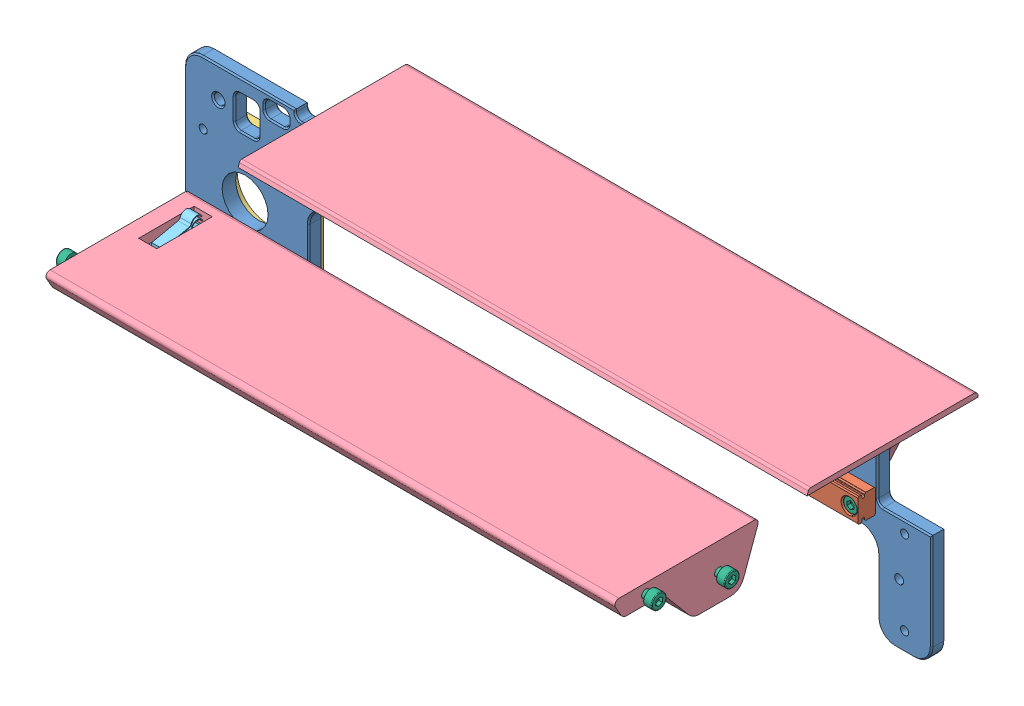
SolidWorks assembly Frame, configuration Default. Lengths in mm.
Overall size (276.5 62.15 134.33).
24 component instances, 6 part files, 47 mates.
Components (placement in the parent):
- Frame plate-1: Frame plate [Default] at (76.4618 160.0978 166.7235) size (276.5 61.25 5)
- Linear rail-1: Linear rail [Default] at (70.7618 160.0978 171.7235) x (0 1 0) z (1 0 0) size (9 6.5 208.9)
- Motor plate-1: Motor plate [Default] at (46.4618 139.3516 166.7235) x (-1 0 0) z (0 0 -1) size (61.5 53.5 20.15)
- Paper tray-1: Paper tray [Default] at (175.2118 177.0978 267.3903) x (0 0 -1) z (1 0 0) size (134.33 22 210.5)
- Limit switch-1: Limit switch [Default] at (79.6118 165.8978 235.3903) x (0 0 -1) z (1 0 0) size (20.1 16 6.3)
- socket head cap screw_din-1: socket head cap screw_din [DIN 912 M3 x 12 --- 12N] at (76.4618 160.0978 177.7235) x (0 0 -1) z (1 0 0) size (15 5.5 5.5)
- socket head cap screw_din-2: socket head cap screw_din [DIN 912 M3 x 12 --- 12N] at (96.4618 160.0978 177.7235) x (0 0 -1) z (1 0 0) size (15 5.5 5.5)
- socket head cap screw_din-3: socket head cap screw_din [DIN 912 M3 x 12 --- 12N] at (116.4618 160.0978 177.7235) x (0 0 -1) z (1 0 0) size (15 5.5 5.5)
- socket head cap screw_din-4: socket head cap screw_din [DIN 912 M3 x 12 --- 12N] at (136.4618 160.0978 177.7235) x (0 0 -1) z (1 0 0) size (15 5.5 5.5)
- socket head cap screw_din-5: socket head cap screw_din [DIN 912 M3 x 12 --- 12N] at (156.4618 160.0978 177.7235) x (0 0 -1) z (1 0 0) size (15 5.5 5.5)
- socket head cap screw_din-6: socket head cap screw_din [DIN 912 M3 x 12 --- 12N] at (176.4618 160.0978 177.7235) x (0 0 -1) z (1 0 0) size (15 5.5 5.5)
- socket head cap screw_din-7: socket head cap screw_din [DIN 912 M3 x 12 --- 12N] at (196.4618 160.0978 177.7235) x (0 0 -1) z (1 0 0) size (15 5.5 5.5)
- socket head cap screw_din-8: socket head cap screw_din [DIN 912 M3 x 12 --- 12N] at (216.4618 160.0978 177.7235) x (0 0 -1) z (1 0 0) size (15 5.5 5.5)
- socket head cap screw_din-9: socket head cap screw_din [DIN 912 M3 x 12 --- 12N] at (236.4618 160.0978 177.7235) x (0 0 -1) z (1 0 0) size (15 5.5 5.5)
- socket head cap screw_din-10: socket head cap screw_din [DIN 912 M3 x 12 --- 12N] at (256.4618 160.0978 177.7235) x (0 0 -1) z (1 0 0) size (15 5.5 5.5)
- socket head cap screw_din-11: socket head cap screw_din [DIN 912 M3 x 8 --- 8N] at (276.4618 160.0978 177.7235) x (0 0 -1) z (1 0 0) size (11 5.5 5.5)
- socket head cap screw_din-12: socket head cap screw_din [DIN 912 M3 x 8 --- 8N] at (74.9618 175.3516 154.0735) x (0 -1 0) z (0 0 1) size (11 5.5 5.5)
- socket head cap screw_din-13: socket head cap screw_din [DIN 912 M3 x 8 --- 8N] at (82.4618 175.3516 154.0735) x (0 -1 0) z (0 0 1) size (11 5.5 5.5)
- socket head cap screw_din-14: socket head cap screw_din [DIN 912 M3 x 12 --- 12N] at (64.9618 173.5978 257.5035) size (15 5.5 5.5)
- socket head cap screw_din-15: socket head cap screw_din [DIN 912 M3 x 8 --- 8N] at (64.9618 167.0978 230.5035) size (11 5.5 5.5)
- socket head cap screw_din-16: socket head cap screw_din [DIN 912 M3 x 12 --- 12N] at (285.4618 167.0978 230.5035) x (-1 0 0) z (0 0.924225 0.381849) size (15 5.5 5.5)
- socket head cap screw_din-17: socket head cap screw_din [DIN 912 M3 x 12 --- 12N] at (285.4618 173.5978 257.5035) x (-1 0 0) z (0 0.924225 0.381849) size (15 5.5 5.5)
- socket head cap screw_din-18: socket head cap screw_din [DIN 912 M2.5 x 10 --- 10N] at (73.9618 165.8978 235.3903) size (12.5 4.5 4.5)
- socket head cap screw_din-19: socket head cap screw_din [DIN 912 M2.5 x 10 --- 10N] at (73.9618 165.8978 225.8903) size (12.5 4.5 4.5)
Mates (geometry in assembly coordinates):
- Concentric1: concentric anti-aligned: cylinder of Frame plate-1 through (76.4618 160.0978 171.7235) axis (0 0 -1) radius 1.25; cylinder of Linear rail-1 through (76.4618 160.0978 171.7235) axis (0 0 1) radius 1.75
- Coincident1: coincident anti-aligned: plane of Frame plate-1 through (273.9618 143.5978 171.7235) normal (0 0 1); plane of Linear rail-1 through (279.6618 155.9978 171.7235) normal (0 0 -1)
- Concentric2: concentric aligned: cylinder of Linear rail-1 through (76.4618 160.0978 171.7235) axis (0 0 1) radius 1.75; cylinder of socket head cap screw_din-1 through (76.4618 160.0978 209.4735) axis (0 0 1) radius 2.75
- Coincident2: coincident anti-aligned: plane of Linear rail-1 through (76.4618 160.0978 174.7235) normal (0 0 1); plane of socket head cap screw_din-1 through (76.4618 162.8478 174.7235) normal (0 0 -1)
- Concentric3: concentric aligned: cylinder of Linear rail-1 through (96.4618 160.0978 171.7235) axis (0 0 1) radius 1.75; cylinder of socket head cap screw_din-2 through (96.4618 160.0978 209.4735) axis (0 0 1) radius 2.75
- Coincident3: coincident anti-aligned: plane of Linear rail-1 through (96.4618 160.0978 174.7235) normal (0 0 1); plane of socket head cap screw_din-2 through (96.4618 162.8478 174.7235) normal (0 0 -1)
- Concentric4: concentric aligned: cylinder of Linear rail-1 through (116.4618 160.0978 171.7235) axis (0 0 1) radius 1.75; cylinder of socket head cap screw_din-3 through (116.4618 160.0978 209.4735) axis (0 0 1) radius 2.75
- Coincident4: coincident anti-aligned: plane of Linear rail-1 through (116.4618 160.0978 174.7235) normal (0 0 1); plane of socket head cap screw_din-3 through (116.4618 162.8478 174.7235) normal (0 0 -1)
- Concentric5: concentric aligned: cylinder of Linear rail-1 through (136.4618 160.0978 171.7235) axis (0 0 1) radius 1.75; cylinder of socket head cap screw_din-4 through (136.4618 160.0978 209.4735) axis (0 0 1) radius 2.75
- Coincident5: coincident anti-aligned: plane of Linear rail-1 through (136.4618 160.0978 174.7235) normal (0 0 1); plane of socket head cap screw_din-4 through (136.4618 162.8478 174.7235) normal (0 0 -1)
- Concentric6: concentric aligned: cylinder of Linear rail-1 through (156.4618 160.0978 171.7235) axis (0 0 1) radius 1.75; cylinder of socket head cap screw_din-5 through (156.4618 160.0978 209.4735) axis (0 0 1) radius 2.75
- Coincident6: coincident anti-aligned: plane of Linear rail-1 through (156.4618 160.0978 174.7235) normal (0 0 1); plane of socket head cap screw_din-5 through (156.4618 162.8478 174.7235) normal (0 0 -1)
- Concentric7: concentric aligned: cylinder of Linear rail-1 through (176.4618 160.0978 171.7235) axis (0 0 1) radius 1.75; cylinder of socket head cap screw_din-6 through (176.4618 160.0978 209.4735) axis (0 0 1) radius 2.75
- Coincident7: coincident anti-aligned: plane of Linear rail-1 through (176.4618 160.0978 174.7235) normal (0 0 1); plane of socket head cap screw_din-6 through (176.4618 162.8478 174.7235) normal (0 0 -1)
- Concentric8: concentric aligned: cylinder of Linear rail-1 through (196.4618 160.0978 171.7235) axis (0 0 1) radius 1.75; cylinder of socket head cap screw_din-7 through (196.4618 160.0978 209.4735) axis (0 0 1) radius 2.75
- Coincident8: coincident anti-aligned: plane of Linear rail-1 through (196.4618 160.0978 174.7235) normal (0 0 1); plane of socket head cap screw_din-7 through (196.4618 162.8478 174.7235) normal (0 0 -1)
- Concentric9: concentric aligned: cylinder of Linear rail-1 through (216.4618 160.0978 171.7235) axis (0 0 1) radius 1.75; cylinder of socket head cap screw_din-8 through (216.4618 160.0978 209.4735) axis (0 0 1) radius 2.75
- Coincident9: coincident anti-aligned: plane of Linear rail-1 through (216.4618 160.0978 174.7235) normal (0 0 1); plane of socket head cap screw_din-8 through (216.4618 162.8478 174.7235) normal (0 0 -1)
- Concentric10: concentric aligned: cylinder of Linear rail-1 through (236.4618 160.0978 174.7235) axis (0 0 1) radius 3; cylinder of socket head cap screw_din-9 through (236.4618 160.0978 209.4735) axis (0 0 1) radius 2.75
- Coincident10: coincident anti-aligned: plane of Linear rail-1 through (236.4618 160.0978 174.7235) normal (0 0 1); plane of socket head cap screw_din-9 through (236.4618 162.8478 174.7235) normal (0 0 -1)
- Concentric11: concentric aligned: cylinder of Linear rail-1 through (256.4618 160.0978 171.7235) axis (0 0 1) radius 1.75; cylinder of socket head cap screw_din-10 through (256.4618 160.0978 209.4735) axis (0 0 1) radius 2.75
- Coincident11: coincident anti-aligned: plane of Linear rail-1 through (256.4618 160.0978 174.7235) normal (0 0 1); plane of socket head cap screw_din-10 through (256.4618 162.8478 174.7235) normal (0 0 -1)
- Concentric12: concentric aligned: cylinder of Linear rail-1 through (276.4618 160.0978 171.7235) axis (0 0 1) radius 1.75; cylinder of socket head cap screw_din-11 through (276.4618 160.0978 209.4735) axis (0 0 1) radius 2.75
- Coincident12: coincident anti-aligned: plane of Linear rail-1 through (276.4618 160.0978 174.7235) normal (0 0 1); plane of socket head cap screw_din-11 through (276.4618 162.8478 174.7235) normal (0 0 -1)
- Concentric13: concentric anti-aligned: cylinder of Frame plate-1 through (30.9618 123.8516 171.7235) axis (0 0 -1) radius 1.5; cylinder of MotorPlate-1 through (30.9618 123.8516 163.2235) axis (0 0 1) radius 1.5
- Coincident13: coincident anti-aligned: plane of Frame plate-1 through (273.9618 143.5978 166.7235) normal (0 0 -1); plane of MotorPlate-1 through (75.9618 143.1016 166.7235) normal (0 0 1)
- Concentric14: concentric anti-aligned: cylinder of socket head cap screw_din-2 through (96.4618 160.0978 209.4735) axis (0 0 1) radius 1.5; cylinder of Paper tray-1 through (96.4618 160.0978 166.7235) axis (0 0 -1) radius 1.375
- Coincident14: coincident anti-aligned: plane of Frame plate-1 through (273.9618 143.5978 166.7235) normal (0 0 -1); plane of Paper tray-1 through (280.4618 175.0978 166.7235) normal (0 0 1)
- Concentric15: concentric anti-aligned: cylinder of MotorPlate-1 through (74.9618 172.3516 154.0735) axis (0 -1 0) radius 1.375; cylinder of socket head cap screw_din-12 through (74.9618 207.1016 154.0735) axis (0 1 0) radius 1.5
- Concentric16: concentric anti-aligned: cylinder of MotorPlate-1 through (82.4618 172.3516 154.0735) axis (0 -1 0) radius 1.375; cylinder of socket head cap screw_din-13 through (82.4618 207.1016 154.0735) axis (0 1 0) radius 1.5
- Coincident15: coincident aligned: plane of socket head cap screw_din-12 through (74.9618 175.3516 154.0735) normal (0 1 0); plane of socket head cap screw_din-13 through (82.4618 175.3516 154.0735) normal (0 1 0)
- Lock1: lock: unknown of MotorPlate-1; unknown of socket head cap screw_din-12
- Concentric17: concentric aligned: cylinder of Paper tray-1 through (84.9618 173.5978 257.5035) axis (-1 0 0) radius 1.375; cylinder of socket head cap screw_din-14 through (33.2118 173.5978 257.5035) axis (-1 0 0) radius 2.75
- Concentric18: concentric aligned: cylinder of Paper tray-1 through (84.9618 167.0978 230.5035) axis (-1 0 0) radius 1.375; cylinder of socket head cap screw_din-15 through (33.2118 167.0978 230.5035) axis (-1 0 0) radius 2.75
- Concentric19: concentric aligned: cylinder of Paper tray-1 through (265.4618 167.0978 230.5035) axis (1 0 0) radius 1.375; cylinder of socket head cap screw_din-16 through (317.2118 167.0978 230.5035) axis (1 0 0) radius 2.75
- Concentric20: concentric aligned: cylinder of Paper tray-1 through (265.4618 173.5978 257.5035) axis (1 0 0) radius 1.375; cylinder of socket head cap screw_din-17 through (317.2118 173.5978 257.5035) axis (1 0 0) radius 2.75
- Distance1: distance = 2 mm anti-aligned: plane of Paper tray-1 through (280.4618 175.5978 267.3903) normal (1 0 0); plane of socket head cap screw_din-17 through (282.4618 172.5477 260.0452) normal (-1 0 0)
- Coincident19: coincident aligned: plane of socket head cap screw_din-16 through (285.4618 167.0978 230.5035) normal (1 0 0); plane of socket head cap screw_din-17 through (285.4618 173.5978 257.5035) normal (1 0 0)
- Distance2: distance = 2 mm anti-aligned: plane of Paper tray-1 through (69.9618 175.5978 267.3903) normal (-1 0 0); plane of socket head cap screw_din-14 through (67.9618 176.3478 257.5035) normal (1 0 0)
- Coincident20: coincident aligned: plane of socket head cap screw_din-14 through (64.9618 173.5978 257.5035) normal (-1 0 0); plane of socket head cap screw_din-15 through (64.9618 167.0978 230.5035) normal (-1 0 0)
- Width1: width aligned: plane of Paper tray-1 through (82.9618 155.0978 220.3903) normal (-1 0 0); plane of Limit switch-1 through (76.2618 155.0978 220.3903) normal (1 0 0); plane of Paper tray-1 through (76.4618 165.8978 235.3903) normal (-1 0 0); plane of Limit switch-1 through (82.7618 165.8978 235.3903) normal (1 0 0)
- Width2: width aligned: plane of Paper tray-1 through (76.2618 155.0978 220.3903) normal (0 0 1); plane of Limit switch-1 through (76.2618 155.0978 240.8903) normal (0 0 -1); plane of Paper tray-1 through (82.7618 173.5978 240.6903) normal (0 0 1); plane of Limit switch-1 through (82.7618 172.9978 220.5903) normal (0 0 -1)
- Distance4: distance = 3.5 mm aligned: plane of Limit switch-1 through (82.7618 173.5978 240.6903) normal (0 1 0); plane of Paper tray-1 through (280.4618 177.0978 267.3903) normal (0 1 0)
- Concentric21: concentric aligned: cylinder of Limit switch-1 through (82.7618 165.8978 235.3903) axis (-1 0 0) radius 1.25; cylinder of socket head cap screw_din-18 through (42.2118 165.8978 235.3903) axis (-1 0 0) radius 2.25
- Coincident21: coincident anti-aligned: plane of Limit switch-1 through (76.4618 165.8978 235.3903) normal (-1 0 0); plane of socket head cap screw_din-18 through (76.4618 168.1478 235.3903) normal (1 0 0)
- Concentric22: concentric aligned: cylinder of Limit switch-1 through (82.7618 165.8978 225.8903) axis (-1 0 0) radius 1.25; cylinder of socket head cap screw_din-19 through (42.2118 165.8978 225.8903) axis (-1 0 0) radius 2.25
- Coincident22: coincident anti-aligned: plane of Limit switch-1 through (76.4618 165.8978 235.3903) normal (-1 0 0); plane of socket head cap screw_din-19 through (76.4618 168.1478 225.8903) normal (1 0 0)
